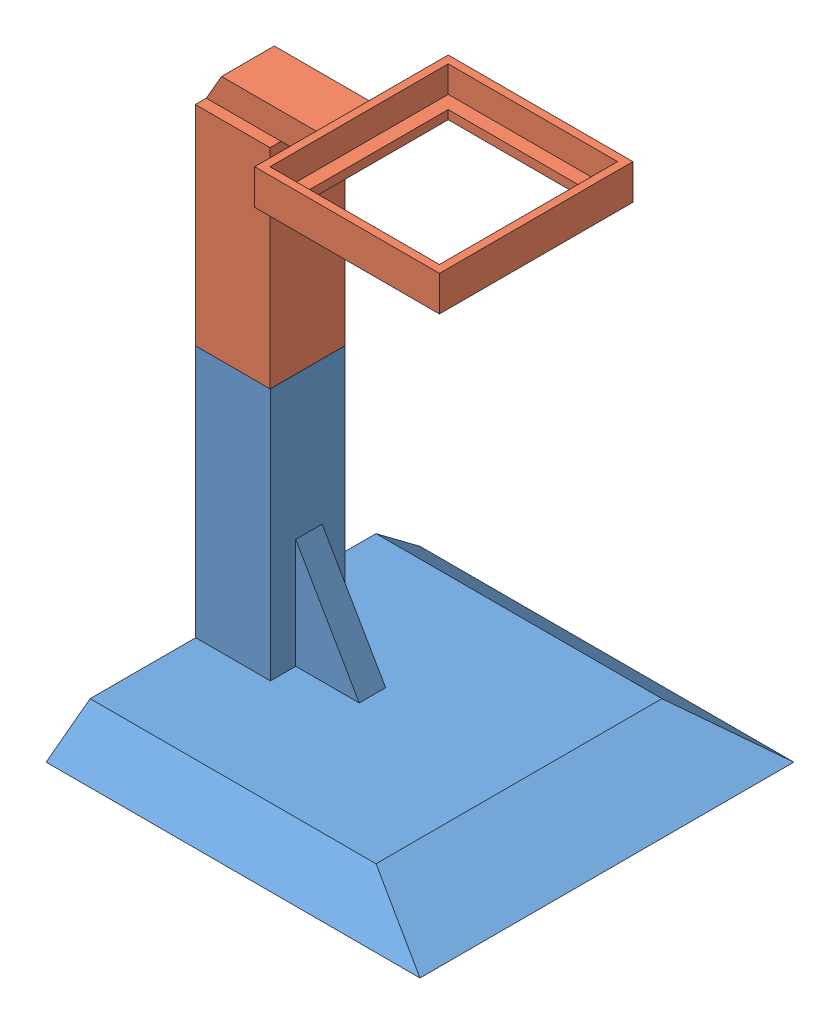
SolidWorks assembly RFID_Stand_Assembly, configuration Default. Lengths in mm.
Overall size (85.03 120.51 85).
2 component instances, 2 part files, 3 mates.
Components (placement in the parent):
- RFID_Stand_Base-1: RFID_Stand_Base [Default] at (27.9565 11.4809 67.4913) size (85 65 85)
- RFID_Stand_Upper-1: RFID_Stand_Upper [Default] at (-6.069 51.4866 67.5494) size (69 80.5 44)
Mates (geometry in assembly coordinates):
- LimitDistance5: limit distance = 0.4582 mm: plane of RFID_Stand_Upper-1 through (-6.069 76.4866 71.9494) normal (0 0 -1); plane of RFID_Stand_Base-1 through (27.9565 51.4809 71.4913) normal (0 0 1)
- LimitDistance6: limit distance = 0.3745 mm: plane of RFID_Stand_Upper-1 through (-13.169 76.4866 67.5494) normal (-1 0 0); plane of RFID_Stand_Base-1 through (-13.5435 51.4809 67.4913) normal (1 0 0)
- LimitDistance7: limit distance = 0.0057 mm: plane of RFID_Stand_Upper-1 through (-6.069 51.4866 67.5494) normal (0 -1 0); plane of RFID_Stand_Base-1 through (27.9565 51.4809 67.4913) normal (0 1 0)
